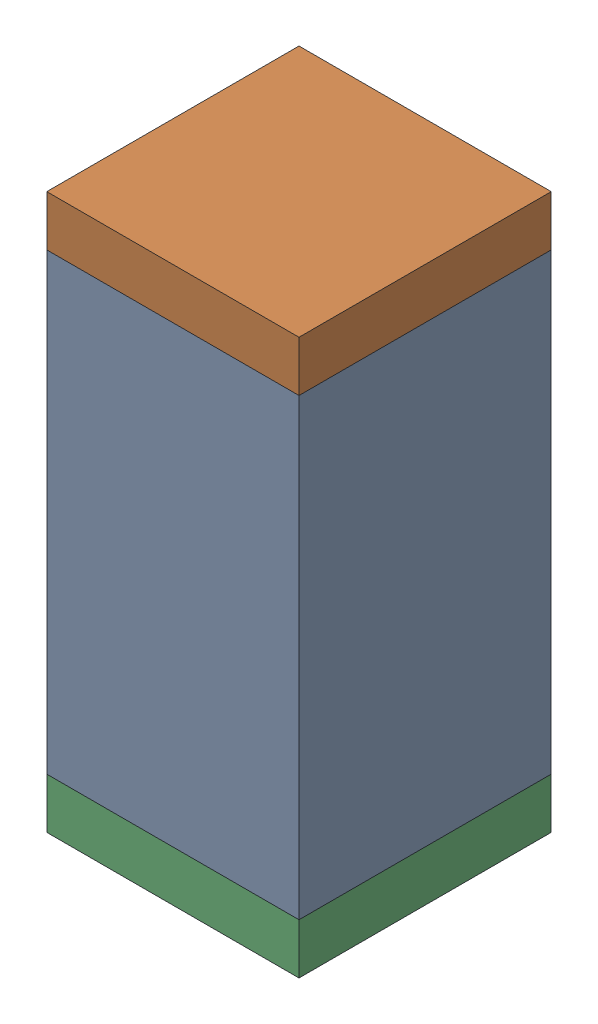
SolidWorks assembly C103, configuration Default. Lengths in mm.
Overall size (0.5 1.1 0.5).
6 component instances, 2 part files, 0 mates.
Components (placement in the parent):
- 791586336-1: 791586336 [Default] at (122.55 70.55 0) size (0.5 0.9 0.5)
  - Extruded_8-1: Extruded_8 [Default] at origin size (0.5 0.9 0.5)
- 810157360-1: 810157360 [Default] at (122.55 71.05 0) size (0.5 0.1 0.5)
  - Extruded_9-1: Extruded_9 [Default] at origin size (0.5 0.1 0.5)
- 810157360-2: 810157360 [Default] at (122.55 70.05 0) size (0.5 0.1 0.5)
  - Extruded_9-1: Extruded_9 [Default] at origin size (0.5 0.1 0.5)
